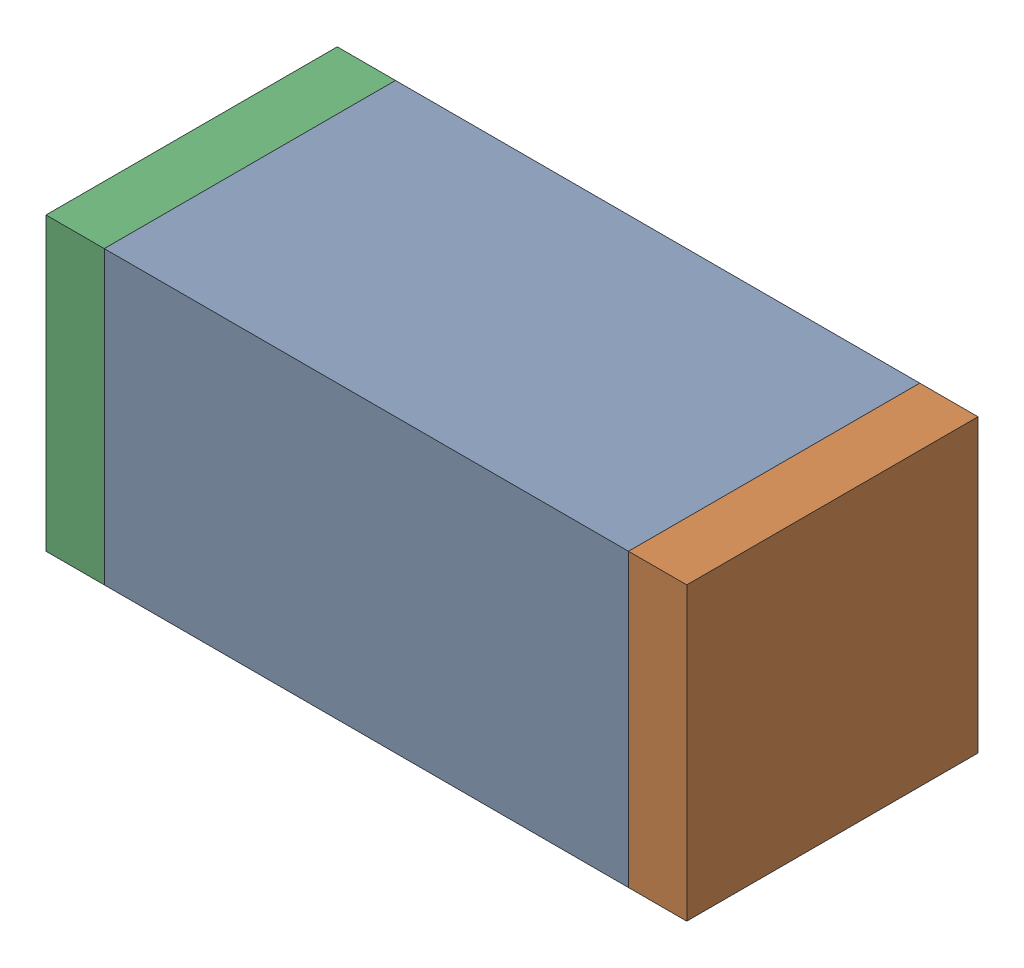
SolidWorks assembly C89, configuration Default. Lengths in mm.
Overall size (1.1 0.5 0.5).
6 component instances, 2 part files, 0 mates.
Components (placement in the parent):
- 836749680-1: 836749680 [Default] at (116 65.4 0) size (0.9 0.5 0.5)
  - Extruded_4-1: Extruded_4 [Default] at origin size (0.9 0.5 0.5)
- 810156080-1: 810156080 [Default] at (116.5 65.4 0) size (0.1 0.5 0.5)
  - Extruded_5-1: Extruded_5 [Default] at origin size (0.1 0.5 0.5)
- 810156080-2: 810156080 [Default] at (115.5 65.4 0) size (0.1 0.5 0.5)
  - Extruded_5-1: Extruded_5 [Default] at origin size (0.1 0.5 0.5)
